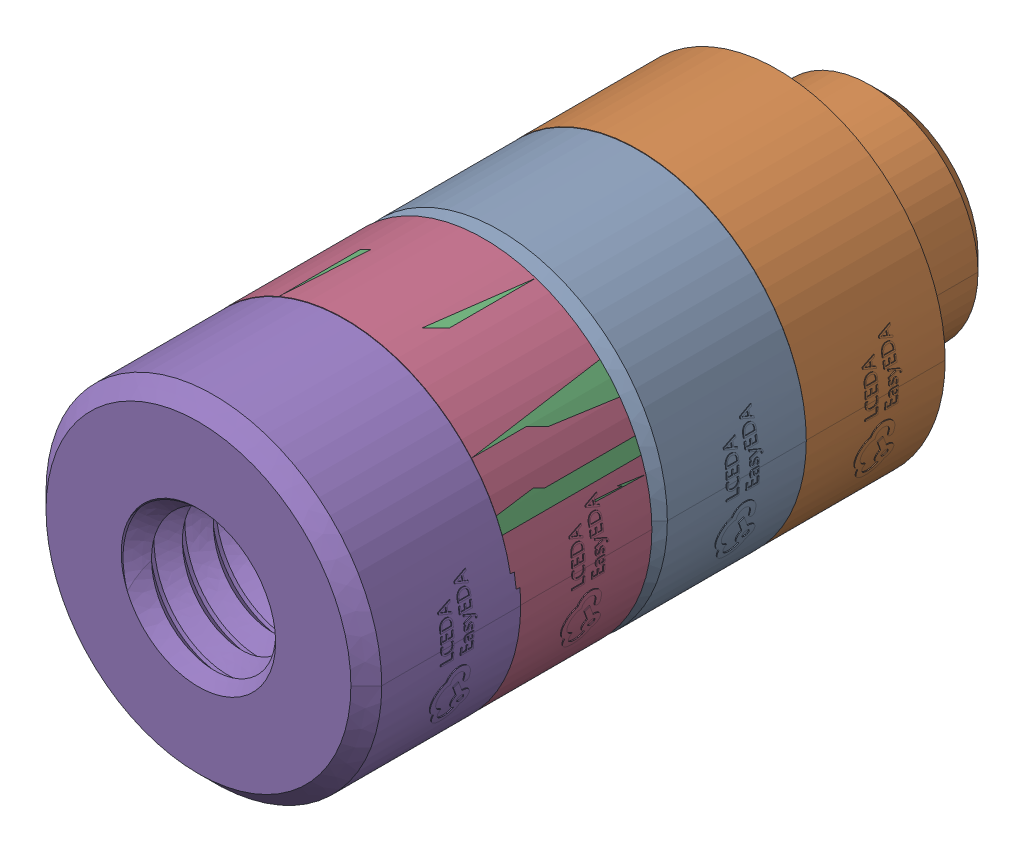
SolidWorks assembly Hole2, configuration Défaut. Lengths in mm.
Overall size (4.36 4.35 8.92).
5 component instances, 1 part files, 0 mates.
Components (placement in the parent):
- SMTWE2055MTJ-1: SMTWE2055MTJ [Défaut] at (71.8005 -43.9084 0.2) x (1 0 0) z (0 0 1) size (4.36 4.35 3.42)
- SMTWE2055MTJ-2: SMTWE2055MTJ [Défaut] at (71.8 -43.9045 -1.6) x (1 0 0) z (0 0 1) size (4.36 4.35 3.42)
- SMTWE2055MTJ-3: SMTWE2055MTJ [Défaut] at (71.8 -43.9045 2.2) x (1 0 0) z (0 0 1) size (4.36 4.35 3.42)
- SMTWE2055MTJ-4: SMTWE2055MTJ [Défaut] at (71.8 -43.9045 2.2) x (1 0 0) z (0 0 1) size (4.36 4.35 3.42)
- SMTWE2055MTJ-5: SMTWE2055MTJ [Défaut] at (71.8005 -43.9084 3.9) x (1 0 0) z (0 0 1) size (4.36 4.35 3.42)
